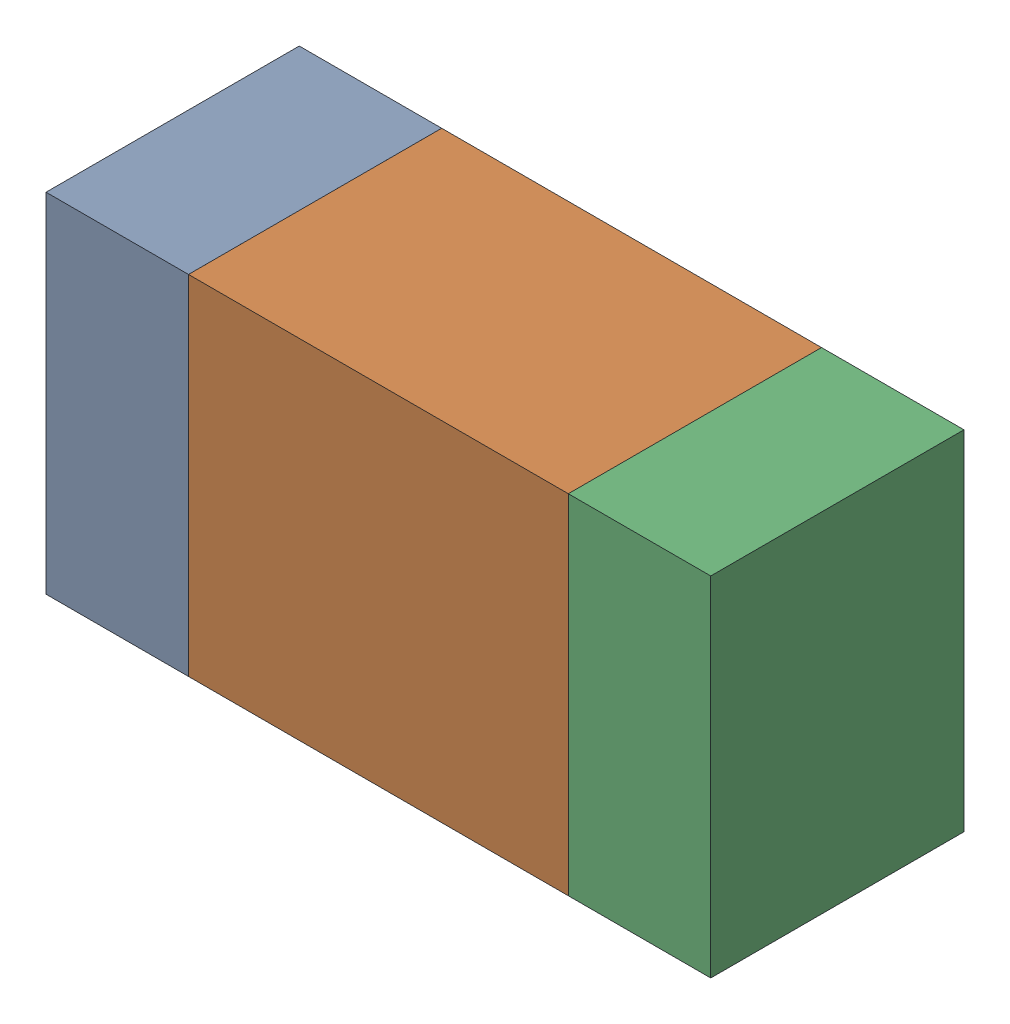
SolidWorks assembly R416PCB, configuration Default. Lengths in mm.
Overall size (1.05 0.55 0.4).
6 component instances, 2 part files, 0 mates.
Components (placement in the parent):
- 854785432-1: 854785432 [Default] at (112.2874 83.0999 0) size (0.22 0.55 0.4)
  - Extruded-1: Extruded [Default] at origin size (0.22 0.55 0.4)
- 854785568-1: 854785568 [Default] at (112.6999 83.0999 0) size (0.6 0.55 0.4)
  - Extruded_2-1: Extruded_2 [Default] at origin size (0.6 0.55 0.4)
- 854785432-2: 854785432 [Default] at (113.1124 83.0999 0) size (0.22 0.55 0.4)
  - Extruded-1: Extruded [Default] at origin size (0.22 0.55 0.4)
